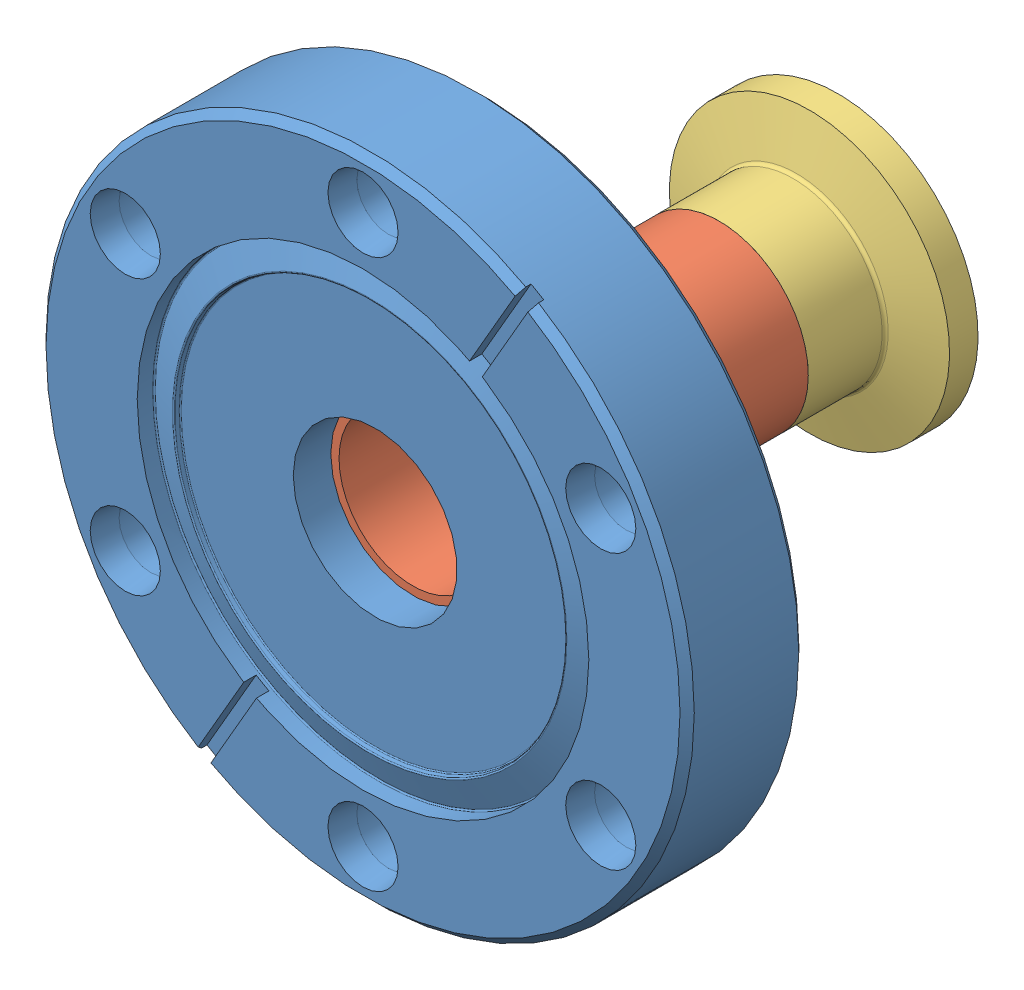
SolidWorks assembly 730001, configuration Default. Lengths in mm.
Overall size (69.34 69.34 50.8).
3 component instances, 3 part files, 4 mates.
Components (placement in the parent):
- 110011-1: 110011 [Default] at (19.5558 39.66 47.8551) size (69.34 69.34 12.7)
- 940131-1: 940131 [Default] at (19.5558 39.66 22.4551) size (19.05 19.05 32.79)
- 713001-1: 713001 [Default] at (19.5558 39.66 9.7551) x (-0.324913 0.945744 0) z (0 0 1) size (29.97 29.97 14.22)
Mates (geometry in assembly coordinates):
- Coincident1: coincident anti-aligned: plane of 110011-1 through (29.2078 39.66 55.2465) normal (0 0 -1); plane of 940131-1 through (19.5558 39.66 55.2465) normal (0 0 1)
- Concentric1: concentric aligned: cylinder of 110011-1 through (19.5558 39.66 47.8551) axis (0 0 -1) radius 8.763; cylinder of 940131-1 through (19.5558 39.66 55.2465) axis (0 0 -1) radius 9.525
- Coincident2: coincident anti-aligned: plane of 940131-1 through (19.5558 39.66 22.4551) normal (0 0 -1); plane of 713001-1 through (16.7911 47.7073 22.4551) normal (0 0 1)
- Concentric2: concentric aligned: cylinder of 940131-1 through (19.5558 39.66 55.2465) axis (0 0 -1) radius 9.525; cylinder of 713001-1 through (19.5558 39.66 9.7551) axis (0 0 -1) radius 9.525
